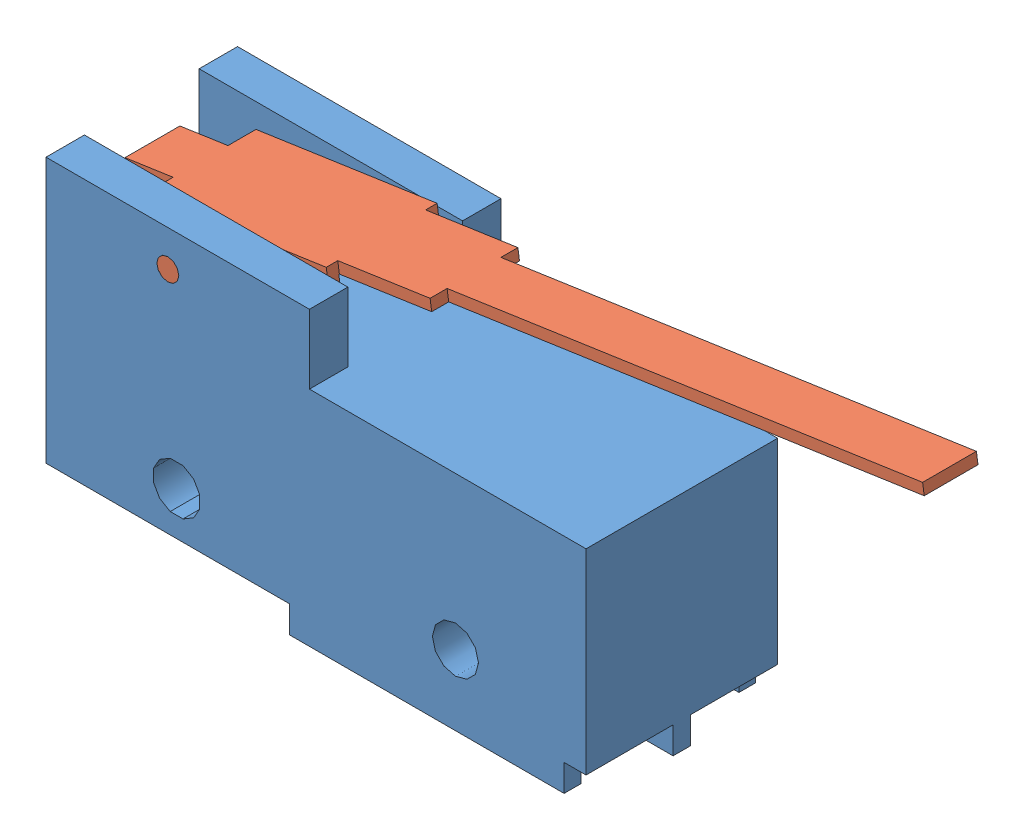
SolidWorks assembly OMRON-Sample_Basic_Switch, configuration Default. Lengths in mm.
Overall size (73.75 36.05 17.45).
2 component instances, 2 part files, 3 mates.
Components (placement in the parent):
- OMRON-Sample_Basic_Switch_Z_15GW_BASE_Sample-1: OMRON-Sample_Basic_Switch_Z_15GW_BASE_Sample [Default] at origin size (49.2 26.6 17.45)
- OMRON-Sample_Basic_Switch_Z_15GW_ACTUATOR_Sample-1: OMRON-Sample_Basic_Switch_Z_15GW_ACTUATOR_Sample [Default] at (-26.2 16.9 0) x (0.9998 -0.019976 0) z (0 0 1) size (72.55 15.49 17.45)
Mates (geometry in assembly coordinates):
- Coincident1: coincident aligned: plane of OMRON-Sample_Basic_Switch_Z_15GW_BASE_Sample-1 through (0 0 0) normal (0 0 1); plane of OMRON-Sample_Basic_Switch_Z_15GW_ACTUATOR_Sample-1 through (-26.2 16.9 0) normal (0 0 1)
- Concentric1: concentric aligned: cylinder of OMRON-Sample_Basic_Switch_Z_15GW_BASE_Sample-1 through (-26.2 16.9 8.725) axis (0 0 -1) radius 1; cylinder of OMRON-Sample_Basic_Switch_Z_15GW_ACTUATOR_Sample-1 through (-26.2 16.9 8.725) axis (0 0 -1) radius 1
- Distance1: distance = 28.2 mm anti-aligned: plane of OMRON-Sample_Basic_Switch_Z_15GW_BASE_Sample-1; line of OMRON-Sample_Basic_Switch_Z_15GW_ACTUATOR_Sample-1 through (36.2865 28.2 2.45) axis (0 0 -1)
